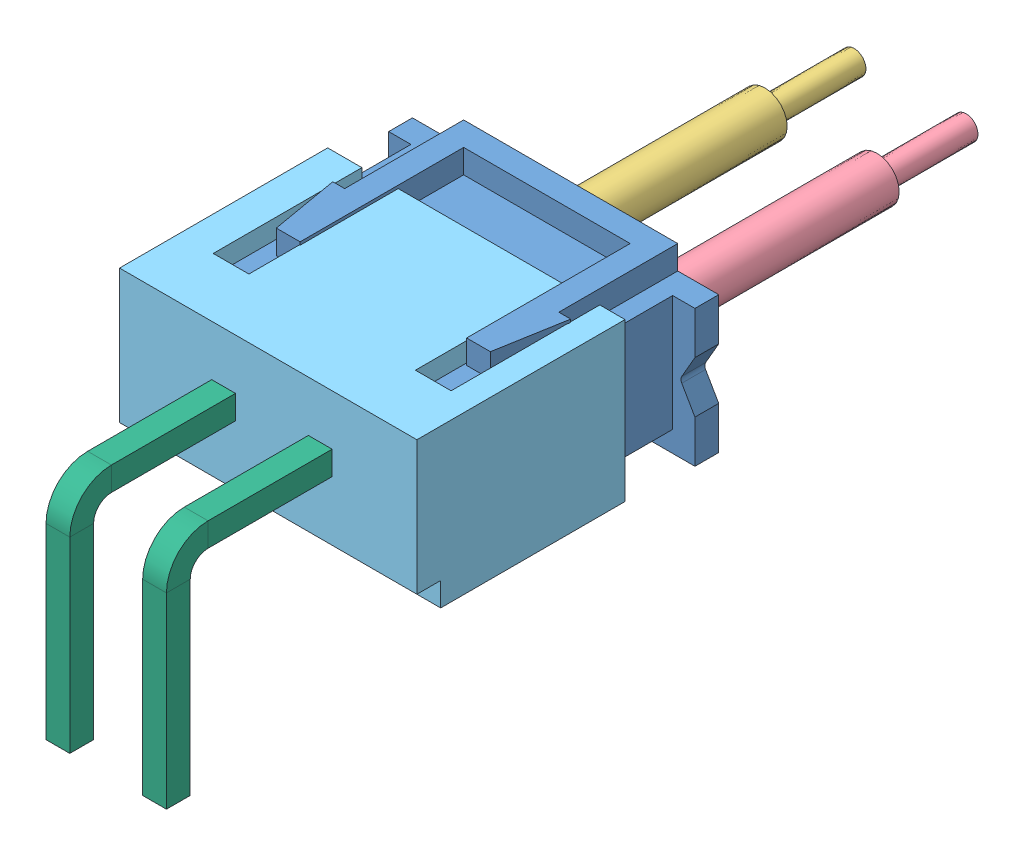
SolidWorks assembly Assem1, configuration Default. Lengths in mm.
Overall size (10.3 9.7 26.8).
8 component instances, 6 part files, 16 mates.
Components (placement in the parent):
- JST - XH MALE 2 pin-1: JST - XH MALE 2 pin [Default] at (3.2913 6.8305 7.2095) size (10.3 5.4 8.4)
- Part1-2: Part1 [Default] at (5.5413 7.1769 13.5095) x (1 0 0) z (0 1 0) size (1.8 6 3.23)
- Part1-3: Part1 [Default] at (1.7913 7.1769 13.5095) x (1 0 0) z (0 1 0) size (1.8 6 3.23)
- Part5-1: Part5 [Default] at (1.7801 6.8159 -1.8049) size (1.5 1.5 16)
- Part4-1: Part4 [Default] at (5.5341 6.7843 -1.817) size (1.5 1.5 16)
- Part 10-1: Part 10 [Default] at (3.2913 7.0305 9.4095) x (-1 0 0) z (0 1 0) size (10 7 5.3)
- Part3-1: Part3 [Default] at (5.0413 7.5805 21.5825) x (0 0 1) z (-1 0 0) size (9.7 7.9 0.8)
- Part3-2: Part3 [Default] at (1.7913 7.5805 21.5825) x (0 0 1) z (-1 0 0) size (9.7 7.9 0.8)
Mates (geometry in assembly coordinates):
- Width1: width anti-aligned: plane of ? through (6.4413 -1.1015 2.8696) normal (1 0 0); plane of ? through (4.6413 -1.1015 2.8696) normal (-1 0 0); plane of JST - XH MALE 2 pin-1 through (6.6413 8.5769 13.9095) normal (-1 0 0); plane of JST - XH MALE 2 pin-1 through (4.4413 8.5769 13.9095) normal (1 0 0)
- Width3: width anti-aligned: plane of Part1-2 through (6.4413 6.0269 11.4095) normal (1 0 0); plane of Part1-2 through (4.6413 6.0269 11.4095) normal (-1 0 0); plane of JST - XH MALE 2 pin-1 through (6.6413 8.5769 13.9095) normal (-1 0 0); plane of JST - XH MALE 2 pin-1 through (4.4413 8.5769 13.9095) normal (1 0 0)
- Width4: width anti-aligned: plane of Part1-2 through (4.6413 8.3269 11.4095) normal (0 1 0); plane of Part1-2 through (4.6413 6.0269 11.4095) normal (0 -1 0); plane of JST - XH MALE 2 pin-1 through (4.4413 8.5769 13.9095) normal (0 -1 0); plane of JST - XH MALE 2 pin-1 through (4.4413 5.7769 13.9095) normal (0 1 0)
- Distance1: distance = 0.4 mm anti-aligned: plane of JST - XH MALE 2 pin-1 through (3.2913 6.8305 13.9095) normal (0 0 -1); plane of Part1-2 through (5.5413 7.1769 13.5095) normal (0 0 1)
- Width5: width aligned: plane of Part1-3 through (2.6913 6.0269 11.4095) normal (1 0 0); plane of Part1-3 through (0.8913 6.0269 11.4095) normal (-1 0 0); plane of JST - XH MALE 2 pin-1 through (0.6913 8.5769 13.9095) normal (1 0 0); plane of JST - XH MALE 2 pin-1 through (2.8913 8.5769 13.9095) normal (-1 0 0)
- Width6: width anti-aligned: plane of Part1-3 through (0.8913 6.0269 11.4095) normal (0 -1 0); plane of Part1-3 through (0.8913 8.3269 11.4095) normal (0 1 0); plane of JST - XH MALE 2 pin-1 through (2.1913 5.7769 13.9095) normal (0 1 0); plane of JST - XH MALE 2 pin-1 through (0.6913 8.5769 13.9095) normal (0 -1 0)
- Distance2: distance = 0.4 mm anti-aligned: plane of Part1-3 through (1.7913 7.1769 13.5095) normal (0 0 1); plane of JST - XH MALE 2 pin-1 through (3.2913 6.8305 13.9095) normal (0 0 -1)
- Width7: width anti-aligned: plane of Part 10-1 through (-1.1087 5.0305 14.4095) normal (1 0 0); plane of Part 10-1 through (7.6913 5.0305 14.4095) normal (-1 0 0); plane of JST - XH MALE 2 pin-1 through (-1.1087 4.6805 14.2095) normal (-1 0 0); plane of JST - XH MALE 2 pin-1 through (7.6913 4.6805 14.2095) normal (1 0 0)
- Width8: width anti-aligned: plane of Part 10-1 through (7.6913 5.0305 14.4095) normal (0 1 0); plane of Part 10-1 through (7.6913 9.0305 14.4095) normal (0 -1 0); plane of JST - XH MALE 2 pin-1 through (3.2913 5.0805 7.2095) normal (0 -1 0); plane of JST - XH MALE 2 pin-1 through (-1.1087 8.9805 14.2095) normal (0 1 0)
- LimitDistance1: limit distance = 0 mm anti-aligned: plane of JST - XH MALE 2 pin-1 through (3.2913 6.8305 14.7095) normal (0 0 1); plane of Part 10-1 through (3.2913 7.0305 14.7095) normal (0 0 -1)
- Coincident2: coincident anti-aligned: plane of Part 10-1 through (4.6413 7.9805 6.4095) normal (0 -1 0); plane of Part3-1 through (5.4413 7.9805 20.5825) normal (0 1 0)
- Coincident3: coincident anti-aligned: plane of Part 10-1 through (5.4413 7.9805 6.4095) normal (-1 0 0); plane of Part3-1 through (5.4413 7.9805 20.5825) normal (1 0 0)
- Distance4: distance = 5.5731 mm aligned: plane of Part3-1 through (5.4413 6.5805 21.9825) normal (0 0 1); plane of Part 10-1 through (3.2913 7.0305 16.4095) normal (0 0 1)
- Coincident5: coincident anti-aligned: plane of Part 10-1 through (1.3913 7.9805 6.4095) normal (0 -1 0); plane of Part3-2 through (2.1913 7.9805 20.5825) normal (0 1 0)
- Coincident6: coincident anti-aligned: plane of Part 10-1 through (2.1913 7.1805 6.4095) normal (-1 0 0); plane of Part3-2 through (2.1913 7.9805 20.5825) normal (1 0 0)
- Coincident7: coincident aligned: plane of Part3-1 through (5.4413 6.5805 21.9825) normal (0 0 1); plane of Part3-2 through (2.1913 6.5805 21.9825) normal (0 0 1)
